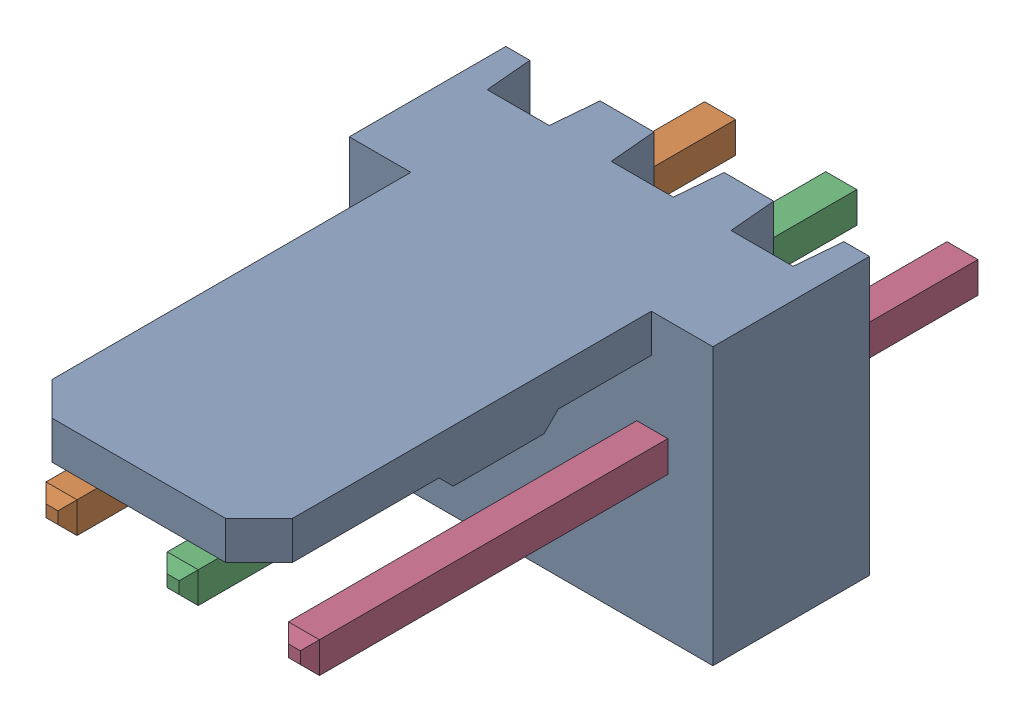
SolidWorks assembly Molex PCB 3 pin v2 v6 (3), configuration Default. Lengths in mm.
Overall size (7.62 5.79 14.92).
4 component instances, 2 part files, 0 mates.
Components (placement in the parent):
- BASE9710016 (1)-1: BASE9710016 (1) [Default] at (2.54 2.895 -8.22) size (7.62 5.79 11.5)
- PINO9710016 (1)-1: PINO9710016 (1) [Default] at (1.27 3.325 -0.72) size (0.65 0.65 14.2)
- PINO9710016 (1)-2: PINO9710016 (1) [Default] at (3.81 3.325 -0.72) size (0.65 0.65 14.2)
- PINO9710016 (1)-3: PINO9710016 (1) [Default] at (6.35 3.325 -0.72) size (0.65 0.65 14.2)
